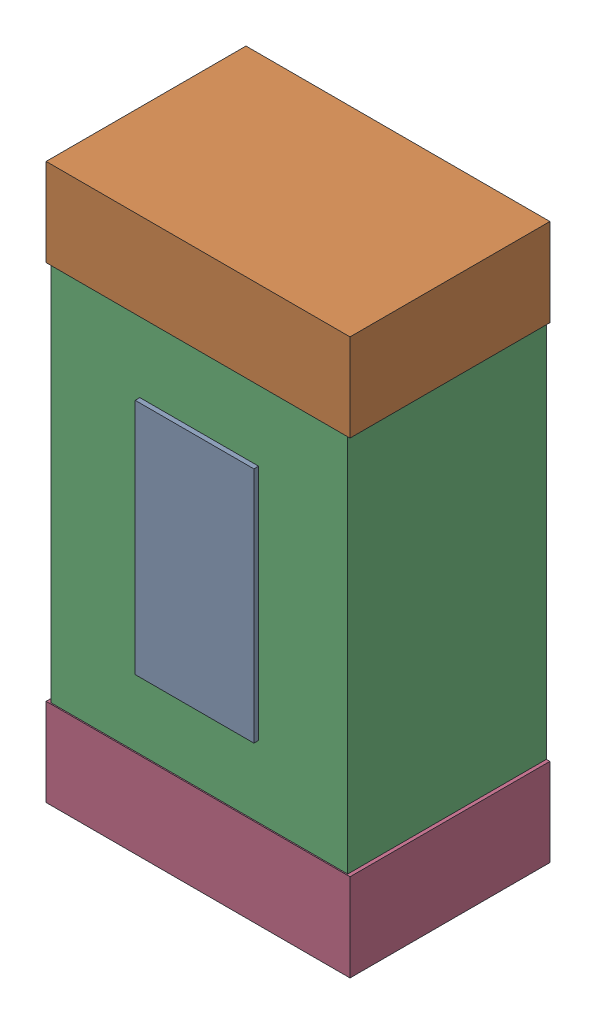
SolidWorks assembly TLEDKanaloa_v2.0.0_Power, configuration Default. Lengths in mm.
Overall size (1.3 2.38 0.87).
8 component instances, 3 part files, 0 mates.
Components (placement in the parent):
- 440440848-1: 440440848 [Default] at (58.65 97.85 0) size (0.51 1.02 0.87)
  - Extruded_4-1: Extruded_4 [Default] at origin size (0.51 1.02 0.87)
- 330415056-1: 330415056 [Default] at (58.65 98.85 0) size (1.3 0.38 0.85)
  - Extruded_2-1: Extruded_2 [Default] at origin size (1.3 0.38 0.85)
- 352877008-1: 352877008 [Default] at (58.65 97.85 0) size (1.27 2.2 0.85)
  - Extruded_3-1: Extruded_3 [Default] at origin size (1.27 2.2 0.85)
- 330415056-2: 330415056 [Default] at (58.65 96.85 0) size (1.3 0.38 0.85)
  - Extruded_2-1: Extruded_2 [Default] at origin size (1.3 0.38 0.85)
